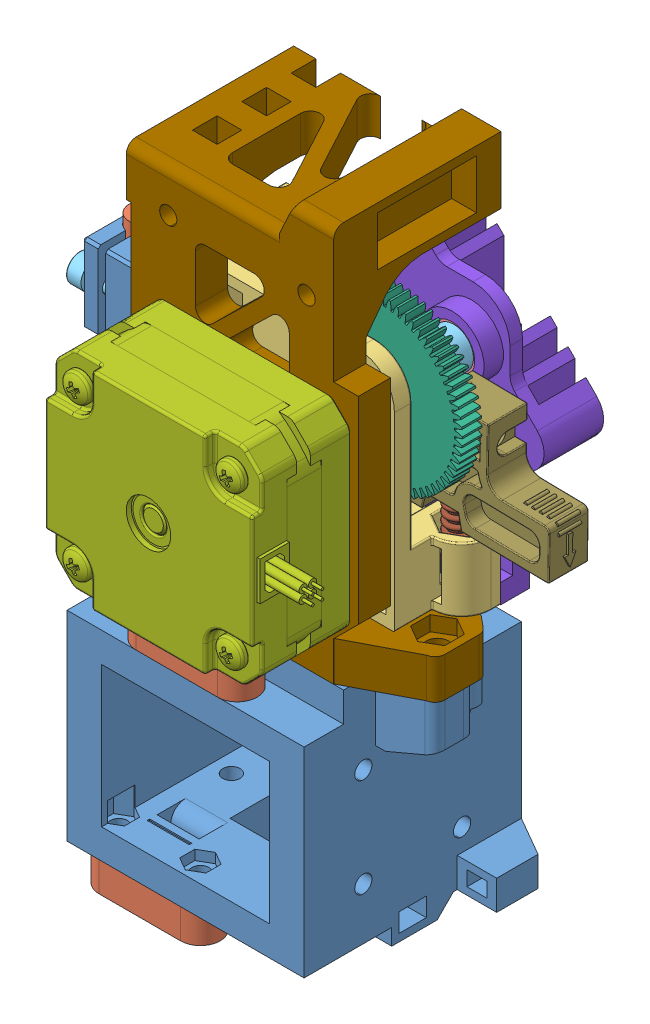
SolidWorks assembly X_Assembly, configuration Default. Lengths in mm.
Overall size (154.04 196.18 164.06).
79 component instances, 47 part files, 59 mates.
Components (placement in the parent):
- BlockAssem-1: BlockAssem [Default] at origin size (10 27 45.5) (hidden)
  - Main Block-1: Main Block [Default] at (169.1827 226.6144 359.262) x (0 0 1) z (1 0 0) size (32 27 10)
  - Green End Cap-1: Green End Cap [Default] at (174.1827 226.6144 343.262) x (0 1 0) z (0 0 -1) size (27 10 5)
  - Red End Cap-1: Red End Cap [Default] at (174.1827 226.6144 338.262) x (0 1 0) z (0 0 -1) size (27 10 1)
  - Green End Cap-2: Green End Cap [Default] at (174.1827 226.6144 375.262) x (0 -1 0) z (0 0 1) size (27 10 5)
  - Red End Cap-2: Red End Cap [Default] at (174.1827 226.6144 380.262) x (0 -1 0) z (0 0 1) size (27 10 1) (hidden)
  - Button M3x8-1: Button M3x8 [Default] at (177.1827 219.6144 381.762) x (0.381849 -0.924225 0) z (0 0 -1) size (3 3 7)
  - Button M3x8-2: Button M3x8 [Default] at (177.1827 233.6144 382.262) x (0.381849 -0.924225 0) z (0 0 -1) size (3 3 7)
  - Button M3x8-3: Button M3x8 [Default] at (177.1827 219.6144 336.762) x (-0.381849 0.924225 0) z (0 0 1) size (3 3 7)
  - Button M3x8-5: Button M3x8 [Default] at (177.1827 233.6144 336.762) x (-0.381849 0.924225 0) z (0 0 1) size (3 3 7)
- X_Carriadge-1: X_Carriadge [Default] at (179.1827 224.5695 363.3255) x (0 0 -1) z (0 -1 0) size (44 72 49.8)
- BeltClamp-1: BeltClamp [Default] at (156.1827 199.4844 345.262) x (0 -1 0) z (0 0 1) size (6 24.6 8)
- BeltClamp-2: BeltClamp [Default] at (148.6827 199.4844 381.262) x (0 -1 0) z (0 0 1) size (6 24.6 8)
- BeltClamp-3: BeltClamp [Default] at (157.1827 245.9844 337.262) x (0 -1 0) z (0 0 -1) size (6 24.6 8)
- BeltClamp-4: BeltClamp [Default] at (156.1827 245.9844 381.262) x (0 -1 0) z (0 0 1) size (6 24.6 8)
- e3d titan areo 1.75-1: e3d titan areo 1.75 [Default] at (166.6827 282.1144 366.762) x (0 -1 0) z (1 0 0) size (62.33 43.86 89.93)
  - e3d titan areo 1.75.step-1: e3d titan areo 1.75.step [Default] at origin size (64.3 55.51 89.93)
    - Base.step-1: Base.step [Default] at origin size (46 23.41 49.98)
    - 9x5x3mm bearing.step-1: 9x5x3mm bearing.step [Default] at (-15.5 4 15.5) x (1 0 0) z (0 -1 0) size (9 9 3)
    - hobbed wheel.step-1: hobbed wheel.step [Default] at (-15.5 1.6 15.5) x (-0.447437 0 0.894315) z (0 1 0) size (8.6 8.58 20.6)
    - filament gear.step-1: filament gear.step [Default] at (-15.5 8.55 15.5) x (-0.894315 0 -0.447437) z (0 -1 0) size (34 34 4)
    - motor gear.step-1: motor gear.step [Default] at (0 8.5 0) x (-0.681998 0 -0.731354) z (0 -1 0) size (11.99 12.02 9)
    - cover.step-1: cover.step [Default] at (0 24.9 0) x (1 0 0) z (0 0 -1) size (52.63 28.16 55.14)
    - 9x5x3mm bearing.step-2: 9x5x3mm bearing.step [Default] at (-15.5 22.8 15.5) x (1 0 0) z (0 -1 0) size (9 9 3)
    - m3x8.step-1: m3x8.step [Default] at (20.7 13.6 23.3) x (0 0 1) z (0 1 0) size (5.69 9.65 5.69)
    - M3 nut.step-1: M3 nut.step [Default] at (16.7 13.6 23.3) x (0 1 0) z (0 0 1) size (5.49 2.44 6.31)
    - idler spring.step-1: idler spring.step [Default] at (14.287 13.6 23.3) x (0 0 1) z (-1 0 0) size (6.44 6.46 12.03)
    - tensioner.step-1: tensioner.step [Default] at (0 13.6 0) x (0 -1 0) z (0.017452 0 0.999848) size (8.2 21.5 50.88)
    - idler bearing pin.step-1: idler bearing pin.step [Default] at (-5.2287 9.6 15.5936) x (0.999848 0 -0.017452) z (0 1 0) size (3 3 9)
    - idler bearing.step-1: idler bearing.step [Default] at (-5.2287 13.6 15.5936) x (0.999848 0 -0.017452) z (0 1 0) size (10 10 4)
    - guide tube.step-1: guide tube.step [Default] at (-10.9 13.6 -7.9) x (-1 0 0) z (0 0 1) size (10.9 16.1 22.03)
    - ISO 7380 - M3 x 28 v1.step-1: ISO 7380 - M3 x 28 v1.step [Default] at (-15.5 25.94 15.5) x (0 -1 0) z (0 0 1) size (14.65 5.7 5.7)
    - ISO 7380 - M3 x 28 v1.step-2: ISO 7380 - M3 x 28 v1.step [Default] at (15.5 25.94 15.5) x (0 -1 0) z (0 0 1) size (14.65 5.7 5.7)
    - ISO 7380 - M3 x 28 v1.step-3: ISO 7380 - M3 x 28 v1.step [Default] at (15.5 25.94 -15.5) x (0 -1 0) z (0 0 1) size (14.65 5.7 5.7)
    - ISO 7380 - M3 x 28 v1.step-4: ISO 7380 - M3 x 28 v1.step [Default] at (-21.7 25.94 -14.7) x (0 -1 0) z (0 0 -1) size (14.65 5.7 5.7)
    - Fan 40 X 40 X 10 v4.step-1: Fan 40 X 40 X 10 v4.step [Default] at (-2.3 40.465 3.8274) x (0.707107 0 0.707107) z (-0.707107 0 0.707107) size (40 10.58 40) (hidden)
    - E3D v6 HotEnd - Heatbreak.step-1: E3D v6 HotEnd - Heatbreak.step [Default] at (-10.9 13.6 -31.7812) x (0 1 0) z (0 0 -1) size (7 7 21.9)
    - E3D v6 HotEnd - Nozzle.step-1: E3D v6 HotEnd - Nozzle.step [Default] at (-10.9 13.6 -42.2812) x (0 1 0) z (0 0 -1) size (8.08 7 12.5)
    - E3D v6 HotEnd - Heat Block.step-1: E3D v6 HotEnd - Heat Block.step [Default] at (-2.9 -1.9 -38.0312) x (0 1 0) z (1 0 0) size (20 11.5 16)
    - Ceramic Cartridge Heater.step-1: Ceramic Cartridge Heater.step [Default] at (-0.9 6.6 -34.0312) x (0 0 1) z (1 0 0) size (6 18 29.25)
    - Thermistor.step-1: Thermistor.step [Default] at (-7 16.1 -36.0312) x (0 -0.5 0.866025) z (-1 0 0) size (1.5 1.5 7.6)
    - HEXAGON SOCKET HEAD CAP SCREWS_SCB3-4.step-1: HEXAGON SOCKET HEAD CAP SCREWS_SCB3-4.step [Default] at (-2.4 14.6 -33.2312) x (0 1 0) z (1 0 0) size (5.5 5.5 7)
    - HEXAGON SOCKET HEAD CAP SCREWS_SCB3-10.step-1: HEXAGON SOCKET HEAD CAP SCREWS_SCB3-10.step [Default] at (-10.9 0.6 -38.0312) x (0 1 0) z (0 0 -1) size (5.5 5.5 13)
    - Flat Washers_PWF3.step-1: Flat Washers_PWF3.step [Default] at (-2.4 14.6 -33.2312) x (0 1 0) z (1 0 0) size (6 6 0.5)
    - ISO 7380 - M3 x 28 v1.step-5: ISO 7380 - M3 x 28 v1.step [Default] at (-2.3 45.465 26.4548) x (0 -1 0) z (0.707107 0 0.707107) size (14.65 5.7 5.7) (hidden)
    - ISO 7380 - M3 x 28 v1.step-6: ISO 7380 - M3 x 28 v1.step [Default] at (-24.9274 45.465 3.8274) x (0 -1 0) z (0.707107 0 0.707107) size (14.65 5.7 5.7) (hidden)
    - ISO 7380 - M3 x 28 v1.step-7: ISO 7380 - M3 x 28 v1.step [Default] at (-2.3 45.465 -18.8) x (0 -1 0) z (0.707107 0 0.707107) size (14.65 5.7 5.7) (hidden)
    - ISO 7380 - M3 x 28 v1.step-8: ISO 7380 - M3 x 28 v1.step [Default] at (20.3274 45.465 3.8274) x (0 -1 0) z (0.707107 0 0.707107) size (14.65 5.7 5.7) (hidden)
- Nema17Pancake-1: Nema17Pancake [По умолчанию] at (166.6827 282.1144 393.262) x (0 -1 0) z (1 0 0) size (42 40 51.2)
- endstop-1: endstop [Default] at (138.1827 224.3644 346.262) x (0 -1 0) z (1 0 0) size (39.5 18.65 8)
- ExtruderMount18-1: ExtruderMount18 [Default] at (140.1827 252.6144 370.762) x (0 0 1) z (-1 0 0) size (33.89 87 72)
- LJ18A3-1: LJ18A3 [Default] at (139.6375 284.4144 309.297) x (0 0.776316 -0.630344) z (1 0 0) size (25.89 27.37 71.4) (hidden)
  - LJ18A3.step-1: LJ18A3.step [Default] at origin size (30 30 71.4)
    - Sensor.step-1: Sensor.step [Default] at origin size (18.25 18.25 71.4)
    - Nut.step-1: Nut.step [Default] at (69.0679 5.4432 19.5) size (25.89 27.37 3.53)
    - Spacer.step-1: Spacer.step [Default] at (163.1041 9.6725 17.5) size (30 30 1) (hidden)
    - Nut.step-2: Nut.step [Default] at (69.0679 5.4432 11.5) size (25.89 27.37 3.53)
    - Spacer.step-2: Spacer.step [Default] at (163.1041 9.6725 16) size (30 30 1) (hidden)
- LedRing-1: LedRing [Default] at (142.1827 293.0144 353.162) x (0 -0.486968 0.87342) z (0 0.87342 0.486968) size (60 1 60) (hidden)
- DuctFan_12v-1: DuctFan_12v [Default] at (157.6831 335.9144 370.6676) x (-0.999986 0 -0.005255) z (0.005255 0 -0.999986) size (71.63 17.56 112.02) (hidden)
  - fan_12v.step-1: fan_12v.step [Default] at origin size (71.63 17.56 112.02)
    - corpo_topo.step-1: corpo_topo.step [Default] at origin size (51.07 9.32 51.81)
    - corpo_base.step-1: corpo_base.step [Default] at origin size (50.9 8.01 51.63)
    - blade.step-1: blade.step [Default] at origin size (40.62 11 40.62)
    - cabo.step-1: cabo.step [Default] at origin size (46.95 2.25 68.66)
    - conector.step-1: conector.step [Default] at origin size (8.74 5 8.77)
- AeroFanShroud2-1: AeroFanShroud2 [Default] at (166.1827 323.5144 367.662) x (0 -1 0) z (-1 0 0) size (69.61 76 57.92) (hidden)
- Hotend E3D-V6_175-300-1: Hotend E3D-V6_175-300 [Default] at (123.6515 376.0644 350.1397) x (0 0 -1) z (0 -1 0) size (34.25 77.7 41.62) (hidden)
- 2ndExtruderMount-1: 2ndExtruderMount [Default] at (179.6515 351.0644 350.1397) x (0 0 1) z (0 1 0) size (45 28.5 16) (hidden)
- 2ndExtruderMountClamp-1: 2ndExtruderMountClamp [Default] at (179.6515 387.0644 350.1397) x (0 0 -1) z (0 -1 0) size (40 12 12) (hidden)
- DuctFan_12v-2: DuctFan_12v [Default] at (181.6883 181.1141 368.762) x (-0.005255 0.999986 0) z (-0.999986 -0.005255 0) size (71.63 17.56 112.02) (hidden)
  - fan_12v.step-1: fan_12v.step [Default] at origin size (71.63 17.56 112.02)
    - corpo_topo.step-1: corpo_topo.step [Default] at origin size (51.07 9.32 51.81)
    - corpo_base.step-1: corpo_base.step [Default] at origin size (50.9 8.01 51.63)
    - blade.step-1: blade.step [Default] at origin size (40.62 11 40.62)
    - cabo.step-1: cabo.step [Default] at origin size (46.95 2.25 68.66)
    - conector.step-1: conector.step [Default] at origin size (8.74 5 8.77)
- AeroFanShroud2-2-1: AeroFanShroud2-2 [Default] at (186.4618 182.5212 359.262) x (0 0 -1) z (-1 0 0) size (25 49.15 56.5) (hidden)
- 18IductiveHolder-2: 18IductiveHolder [Default] at (180.6375 284.4144 309.297) x (0 0 1) z (0 -1 0) size (34.25 53 24.5) (hidden)
Mates (geometry in assembly coordinates):
- Concentric1: concentric anti-aligned: cylinder of BlockAssem-1/Main Block-1 through (174.1827 236.6144 369.262) axis (1 0 0) radius 1.35; cylinder of X_Carriadge-1 through (184.1827 236.6144 369.262) axis (-1 0 0) radius 1.75
- Concentric2: concentric anti-aligned: cylinder of BlockAssem-1/Main Block-1 through (174.1827 216.6144 369.262) axis (1 0 0) radius 1.375; cylinder of X_Carriadge-1 through (184.1827 216.6144 369.262) axis (-1 0 0) radius 1.75
- Coincident1: coincident anti-aligned: plane of BlockAssem-1/Green End Cap-2 through (179.1827 240.1144 380.262) normal (1 0 0); plane of X_Carriadge-1 through (179.1827 224.5695 363.3255) normal (-1 0 0)
- Concentric3: concentric aligned: cylinder of X_Carriadge-1 through (152.1827 214.1144 341.262) axis (0 -1 0) radius 1.6945; cylinder of BeltClamp-1 through (152.1827 203.1144 341.262) axis (0 -1 0) radius 1.75
- Concentric4: concentric aligned: cylinder of X_Carriadge-1 through (168.6827 214.1144 341.262) axis (0 -1 0) radius 1.6235; cylinder of BeltClamp-1 through (168.6827 203.1144 341.262) axis (0 -1 0) radius 1.75
- Concentric5: concentric aligned: cylinder of X_Carriadge-1 through (144.6827 214.1144 377.262) axis (0 -1 0) radius 1.75; cylinder of BeltClamp-2 through (144.6827 203.1144 377.262) axis (0 -1 0) radius 1.75
- Concentric6: concentric aligned: cylinder of X_Carriadge-1 through (161.1827 214.1144 377.262) axis (0 -1 0) radius 1.75; cylinder of BeltClamp-2 through (161.1827 203.1144 377.262) axis (0 -1 0) radius 1.75
- Concentric7: concentric anti-aligned: cylinder of X_Carriadge-1 through (144.6827 238.6144 341.262) axis (0 1 0) radius 1.75; cylinder of BeltClamp-3 through (144.6827 249.6144 341.262) axis (0 -1 0) radius 1.75
- Concentric8: concentric anti-aligned: cylinder of X_Carriadge-1 through (161.1827 238.6144 341.262) axis (0 1 0) radius 1.75; cylinder of BeltClamp-3 through (161.1827 249.6144 341.262) axis (0 -1 0) radius 1.75
- Concentric9: concentric anti-aligned: cylinder of X_Carriadge-1 through (152.1827 238.6144 377.262) axis (0 1 0) radius 1.75; cylinder of BeltClamp-4 through (152.1827 249.6144 377.262) axis (0 -1 0) radius 1.75
- Concentric10: concentric anti-aligned: cylinder of X_Carriadge-1 through (168.6827 238.6144 377.262) axis (0 1 0) radius 1.75; cylinder of BeltClamp-4 through (168.6827 249.6144 377.262) axis (0 -1 0) radius 1.75
- Parallel1: parallel anti-aligned: plane of X_Carriadge-1 through (184.1827 244.6144 337.262) normal (0 0 -1); plane of e3d titan areo 1.75-1/e3d titan areo 1.75.step-1/Base.step-1 through (167.9827 284.4144 366.762) normal (0 0 1)
- Concentric11: concentric aligned: cylinder of e3d titan areo 1.75-1/e3d titan areo 1.75.step-1/hobbed wheel.step-1 through (182.1827 297.6144 354.862) axis (0 0 1) radius 1.65; cylinder of Nema17Pancake-1 through (182.1827 297.6144 373.262) axis (0 0 1) radius 1.5
- Concentric12: concentric aligned: cylinder of e3d titan areo 1.75-1/e3d titan areo 1.75.step-1/Base.step-1 through (151.1827 266.6144 363.262) axis (0 0 1) radius 1.825; cylinder of Nema17Pancake-1 through (151.1827 266.6144 373.262) axis (0 0 1) radius 1.5
- Parallel4: parallel aligned: plane of X_Carriadge-1 through (184.1827 244.6144 337.262) normal (0 0 -1); plane of endstop-1 through (137.1827 236.6144 338.262) normal (0 0 -1)
- Concentric15: concentric anti-aligned: cylinder of X_Carriadge-1 through (138.1827 239.6144 341.262) axis (1 0 0) radius 2; cylinder of endstop-1 through (137.1827 239.6144 341.262) axis (-1 0 0) radius 1.6
- Coincident16: coincident anti-aligned: plane of X_Carriadge-1 through (138.1827 220.6144 341.262) normal (-1 0 0); plane of endstop-1 through (138.1827 224.3644 346.262) normal (1 0 0)
- Coincident17: coincident aligned: plane of X_Carriadge-1 through (180.1827 250.6144 349.262) normal (-1 0 0); plane of ExtruderMount18-1 through (180.1827 257.6144 349.262) normal (-1 0 0)
- Coincident18: coincident aligned: plane of X_Carriadge-1 through (170.1827 250.6144 349.262) normal (0 0 1); plane of ExtruderMount18-1 through (170.1827 257.6144 349.262) normal (0 0 1)
- Concentric16: concentric anti-aligned: circle of Nema17Pancake-1; cylinder of ExtruderMount18-1 through (182.1827 297.6144 345.262) axis (0 0 1) radius 1.75
- Concentric17: concentric aligned: cylinder of Nema17Pancake-1 through (151.1827 297.6144 373.262) axis (0 0 1) radius 1.5; cylinder of ExtruderMount18-1 through (151.1827 297.6144 345.262) axis (0 0 1) radius 1.75
- Parallel5: parallel aligned: plane of Nema17Pancake-1 through (166.6827 282.1144 393.262) normal (0 0 1); plane of LJ18A3-1/LJ18A3.step-1/Nut.step-2 through (151.1375 291.3426 321.297) normal (0 0 1)
- Coincident30: coincident anti-aligned: plane of DuctFan_12v-1/fan_12v.step-1/corpo_base.step-1 through (132.6827 335.9144 343.662) normal (-1 0 0); plane of AeroFanShroud2-1 through (132.6827 315.5144 362.662) normal (1 0 0)
- Coincident31: coincident anti-aligned: plane of DuctFan_12v-1/fan_12v.step-1/corpo_base.step-1 through (155.5621 335.9144 344.662) normal (0 0 1); plane of AeroFanShroud2-1 through (135.6827 323.5144 344.662) normal (0 0 -1)
- Coincident32: coincident anti-aligned: plane of DuctFan_12v-1/fan_12v.step-1/corpo_topo.step-1 through (159.7166 349.9144 373.5853) normal (0 -1 0); plane of AeroFanShroud2-1 through (135.6827 349.9144 367.662) normal (0 1 0)
- Parallel7: parallel aligned: plane of ExtruderMount18-1 through (142.1827 252.6144 370.762) normal (-1 0 0); plane of AeroFanShroud2-1 through (124.6827 323.5144 367.662) normal (-1 0 0)
- Concentric22: concentric anti-aligned: circle of e3d titan areo 1.75-1/e3d titan areo 1.75.step-1/E3D v6 HotEnd - Nozzle.step-1; circle of AeroFanShroud2-1
- Parallel10: parallel anti-aligned: plane of e3d titan areo 1.75-1/e3d titan areo 1.75.step-1/Base.step-1 through (145.9827 307.4144 366.762) normal (0 1 0); plane of AeroFanShroud2-1 through (169.2879 333.0144 364.662) normal (0 -1 0)
- Concentric24: concentric anti-aligned: circle of e3d titan areo 1.75-1/e3d titan areo 1.75.step-1/E3D v6 HotEnd - Nozzle.step-1; circle of LedRing-1
- Concentric25: concentric anti-aligned: cylinder of Hotend E3D-V6_175-300-1 through (179.1515 376.0644 350.1397) axis (-1 0 0) radius 6; circle of 2ndExtruderMount-1
- Coincident38: coincident anti-aligned: plane of Hotend E3D-V6_175-300-1 through (182.1515 372.5614 345.2685) normal (-1 0 0); plane of 2ndExtruderMount-1 through (182.1515 370.6144 350.1397) normal (1 0 0)
- Coincident39: coincident aligned: plane of e3d titan areo 1.75-1/e3d titan areo 1.75.step-1/E3D v6 HotEnd - Heat Block.step-1 through (128.6515 285.0144 368.662) normal (-1 0 0); plane of Hotend E3D-V6_175-300-1 through (128.6515 372.5644 350.1397) normal (-1 0 0)
- Parallel11: parallel aligned: plane of e3d titan areo 1.75-1/e3d titan areo 1.75.step-1/E3D v6 HotEnd - Heat Block.step-1 through (140.1515 301.0144 368.662) normal (0 0 1); plane of Hotend E3D-V6_175-300-1 through (134.4015 384.0644 358.1397) normal (0 0 1)
- Parallel12: parallel: plane of Hotend E3D-V6_175-300-1 through (134.4015 361.0644 358.1397) normal (0 -1 0); plane of 2ndExtruderMount-1 through (179.6515 351.0644 350.1397) normal (0 -1 0)
- Coincident42: coincident anti-aligned: plane of 2ndExtruderMount-1 through (179.6515 375.0644 350.1397) normal (0 1 0); plane of 2ndExtruderMountClamp-1 through (179.6515 375.0644 350.1397) normal (0 -1 0)
- Concentric26: concentric aligned: cylinder of 2ndExtruderMount-1 through (179.6515 360.0644 363.1397) axis (0 -1 0) radius 2.15; cylinder of 2ndExtruderMountClamp-1 through (179.6515 381.8644 363.1397) axis (0 -1 0) radius 3.75
- Concentric27: concentric aligned: cylinder of 2ndExtruderMount-1 through (179.6515 360.0644 337.1397) axis (0 -1 0) radius 2.15; cylinder of 2ndExtruderMountClamp-1 through (179.6515 381.8644 337.1397) axis (0 -1 0) radius 3.75
- Coincident45: coincident anti-aligned: plane of e3d titan areo 1.75-1/e3d titan areo 1.75.step-1/Base.step-1 through (167.9827 284.4144 366.762) normal (0 0 1); plane of ExtruderMount18-1 through (140.1827 252.6144 366.762) normal (0 0 -1)
- Coincident46: coincident anti-aligned: plane of Nema17Pancake-1 through (166.6827 282.1144 373.262) normal (0 0 -1); plane of ExtruderMount18-1 through (166.1827 257.6144 373.262) normal (0 0 1)
- Coincident49: coincident aligned: plane of ExtruderMount18-1 through (146.6827 321.6144 359.3697) normal (1 0 0); plane of AeroFanShroud2-1 through (146.6827 331.6144 366.8682) normal (1 0 0)
- Coincident50: coincident: plane of ExtruderMount18-1 through (179.1827 330.8644 344.3697) normal (0 0 1); plane of 2ndExtruderMount-1 through (189.1815 330.8644 344.3697) normal (0 0 1)
- Coincident51: coincident: plane of ExtruderMount18-1 through (179.1827 330.8644 364.3697) normal (0 -1 0); plane of 2ndExtruderMount-1 through (189.1815 330.8644 344.3697) normal (0 -1 0)
- Coincident53: coincident anti-aligned: plane of X_Carriadge-1 through (167.1827 246.6144 346.262) normal (0 1 0); plane of BeltClamp-3 through (148.6827 246.6144 337.262) normal (0 -1 0)
- Coincident54: coincident anti-aligned: plane of X_Carriadge-1 through (179.1827 246.6144 363.3255) normal (0 1 0); plane of BeltClamp-4 through (164.6827 246.6144 381.262) normal (0 -1 0)
- Coincident55: coincident anti-aligned: plane of X_Carriadge-1 through (128.1827 252.6144 360.2866) normal (0 1 0); plane of ExtruderMount18-1 through (140.1827 252.6144 370.762) normal (0 -1 0)
- Coincident58: coincident anti-aligned: plane of X_Carriadge-1 through (179.1827 206.1144 363.3255) normal (0 -1 0); plane of BeltClamp-2 through (161.1827 206.1144 377.262) normal (0 1 0)
- Coincident59: coincident anti-aligned: plane of X_Carriadge-1 through (179.1827 206.1144 363.3255) normal (0 -1 0); plane of BeltClamp-1 through (168.6827 206.1144 341.262) normal (0 1 0)
- Coincident60: coincident anti-aligned: plane of X_Carriadge-1 through (179.1827 206.1144 363.3255) normal (0 -1 0); plane of DuctFan_12v-2/fan_12v.step-1/corpo_base.step-1 through (154.6827 206.1144 368.762) normal (0 1 0)
- Coincident63: coincident anti-aligned: plane of X_Carriadge-1 through (172.6827 204.1144 367.762) normal (0 0 1); plane of DuctFan_12v-2/fan_12v.step-1/corpo_base.step-1 through (184.606 179.0805 367.762) normal (0 0 -1)
- Coincident64: coincident anti-aligned: plane of X_Carriadge-1 through (155.6827 204.1144 367.762) normal (-1 0 0); plane of DuctFan_12v-2/fan_12v.step-1/corpo_topo.step-1 through (155.6827 183.2351 368.762) normal (1 0 0)
- Concentric31: concentric aligned: cylinder of DuctFan_12v-2/fan_12v.step-1/corpo_base.step-1 through (160.4618 158.5212 353.762) axis (0 0 1) radius 2; cylinder of AeroFanShroud2-2-1 through (160.4618 158.5212 369.762) axis (0 0 1) radius 1.3
- Coincident65: coincident anti-aligned: plane of DuctFan_12v-2/fan_12v.step-1/corpo_base.step-1 through (184.606 179.0805 368.762) normal (0 0 1); plane of AeroFanShroud2-2-1 through (189.567 185.5212 368.762) normal (0 0 -1)
- Parallel13: parallel aligned: plane of X_Carriadge-1 through (138.1827 220.6144 341.262) normal (-1 0 0); plane of AeroFanShroud2-2-1 through (144.9618 182.5212 359.262) normal (-1 0 0)
- Coincident66: coincident anti-aligned: plane of e3d titan areo 1.75-1/e3d titan areo 1.75.step-1/cover.step-1 through (170.5849 284.4144 331.297) normal (0 0 -1); plane of 18IductiveHolder-2 through (160.6375 284.4144 331.297) normal (0 0 1)
- Concentric32: concentric aligned: cylinder of e3d titan areo 1.75-1/e3d titan areo 1.75.step-1/cover.step-1 through (192.1375 284.4144 331.297) axis (0 0 1) radius 1.4224; cylinder of 18IductiveHolder-2 through (192.1375 284.4144 328.297) axis (0 0 1) radius 1.75
- Parallel15: parallel aligned: plane of e3d titan areo 1.75-1/e3d titan areo 1.75.step-1/cover.step-1 through (145.9827 261.4144 341.862) normal (0 -1 0); plane of 18IductiveHolder-2 through (160.6375 272.1644 309.297) normal (0 -1 0)
- Concentric34: concentric aligned: cylinder of LJ18A3-1/LJ18A3.step-1/Sensor.step-1 through (179.6375 284.4144 309.297) axis (1 0 0) radius 8.5; cylinder of 18IductiveHolder-2 through (160.6375 284.4144 309.297) axis (1 0 0) radius 9.25
- Coincident69: coincident anti-aligned: plane of LJ18A3-1/LJ18A3.step-1/Nut.step-2 through (154.6375 284.4144 309.297) normal (1 0 0); plane of 18IductiveHolder-2 through (154.6375 284.4144 309.297) normal (-1 0 0)
- Coincident71: coincident anti-aligned: plane of ExtruderMount18-1 through (143.1827 293.0144 350.662) normal (-1 0 0); plane of LedRing-1 through (143.1827 293.0144 353.162) normal (1 0 0)
